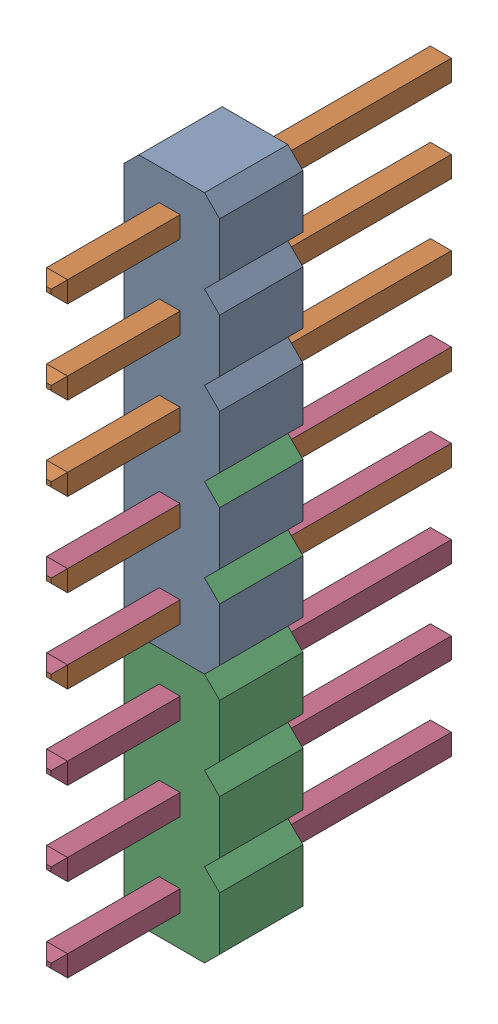
SolidWorks assembly PCB.step, configuration Default. Lengths in mm.
Overall size (2.92 20.32 12.19).
7 component instances, 2 part files, 0 mates.
Components (placement in the parent):
- Free-Models.step-1: Free-Models.step [Default] at origin size (2.92 20.32 12.19)
  - 1240637040.step-1: 1240637040.step [Default] at (97.7778 84.836 -1.6002) x (0 -1 0) z (1 0 0) size (12.7 12.19 2.92)
    - User_Library-PinHeaderX5-1_PinHeaderX5_Body_1.step-1: User_Library-PinHeaderX5-1_PinHeaderX5_Body_1.step [Default] at origin size (12.7 2.54 2.92)
    - User_Library-PinHeaderX5-1_PinHeaderX5_Pins_1.step-1: User_Library-PinHeaderX5-1_PinHeaderX5_Pins_1.step [Default] at origin size (10.8 12.19 0.64)
  - 1240637040.step-2: 1240637040.step [Default] at (97.7778 77.216 -1.6002) x (0 -1 0) z (1 0 0) size (12.7 12.19 2.92)
    - User_Library-PinHeaderX5-1_PinHeaderX5_Body_1.step-1: User_Library-PinHeaderX5-1_PinHeaderX5_Body_1.step [Default] at origin size (12.7 2.54 2.92)
    - User_Library-PinHeaderX5-1_PinHeaderX5_Pins_1.step-1: User_Library-PinHeaderX5-1_PinHeaderX5_Pins_1.step [Default] at origin size (10.8 12.19 0.64)
